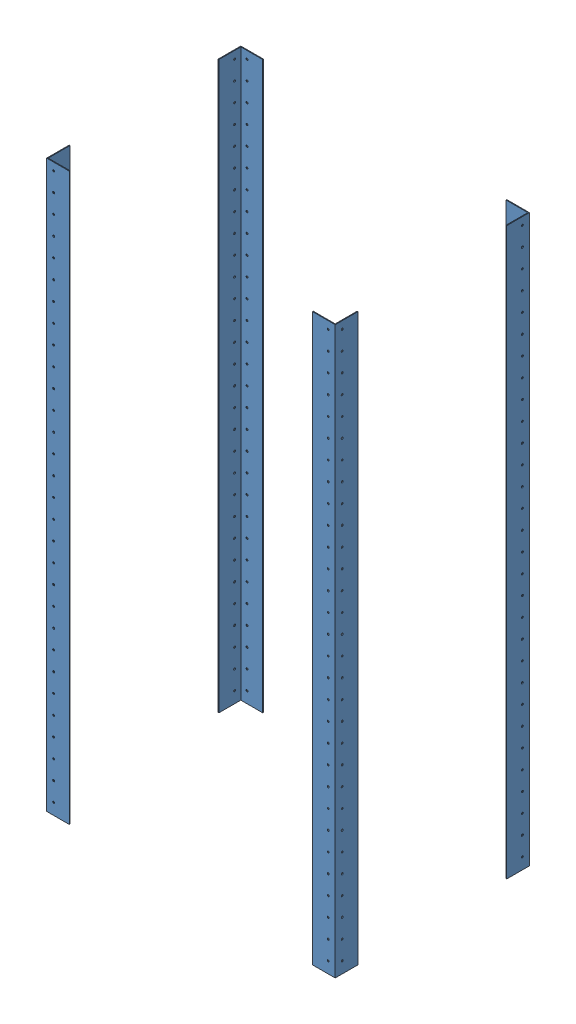
SolidWorks assembly СтеллажПОКУП, configuration По умолчанию. Lengths in mm.
Overall size (765 1500 514.69).
4 component instances, 1 part files, 8 mates.
Components (placement in the parent):
- СтойкаПОКУП-1: СтойкаПОКУП [По умолчанию] at origin size (60 1500 60)
- СтойкаПОКУП-2: СтойкаПОКУП [По умолчанию] at (765 0 0) x (0 0 -1) z (1 0 0) size (60 1500 60)
- СтойкаПОКУП-3: СтойкаПОКУП [По умолчанию] at (0 0 -514.6943) x (0 0 1) z (-1 0 0) size (60 1500 60)
- СтойкаПОКУП-4: СтойкаПОКУП [По умолчанию] at (765 0 -514.6943) x (-1 0 0) z (0 0 -1) size (60 1500 60)
Mates (geometry in assembly coordinates):
- Совпадение2: coincident aligned: plane of СтойкаПОКУП-1 through (0 1500 0) normal (0 0 1); plane of СтойкаПОКУП-2 through (935.5503 1500 0) normal (0 0 1)
- Совпадение3: coincident anti-aligned: plane of СтойкаПОКУП-2 through (995.5503 0 0) normal (0 -1 0); plane of assembly through (0 0 0) normal (0 1 0)
- Совпадение4: coincident anti-aligned: plane of СтойкаПОКУП-4 through (995.5503 0 -514.6943) normal (0 -1 0); plane of assembly through (0 0 0) normal (0 1 0)
- Совпадение5: coincident anti-aligned: plane of СтойкаПОКУП-3 through (0 0 -514.6943) normal (0 -1 0); plane of assembly through (0 0 0) normal (0 1 0)
- Совпадение6: coincident aligned: plane of СтойкаПОКУП-2 through (993.5503 1500 0) normal (-1 0 0); plane of СтойкаПОКУП-4 through (993.5503 1500 -454.6943) normal (-1 0 0)
- Совпадение7: coincident aligned: plane of СтойкаПОКУП-1 through (0 1500 -60) normal (-1 0 0); plane of СтойкаПОКУП-3 through (0 1500 -514.6943) normal (-1 0 0)
- Совпадение8: coincident aligned: plane of СтойкаПОКУП-3 through (60 1500 -514.6943) normal (0 0 -1); plane of СтойкаПОКУП-4 through (995.5503 1500 -514.6943) normal (0 0 -1)
- Расстояние1: distance = 723 mm: cylinder of СтойкаПОКУП-1 through (18.5 1480 -60) axis (0 0 1) radius 2.5; cylinder of СтойкаПОКУП-2 through (746.5 1480 -60) axis (0 0 1) radius 2.5
